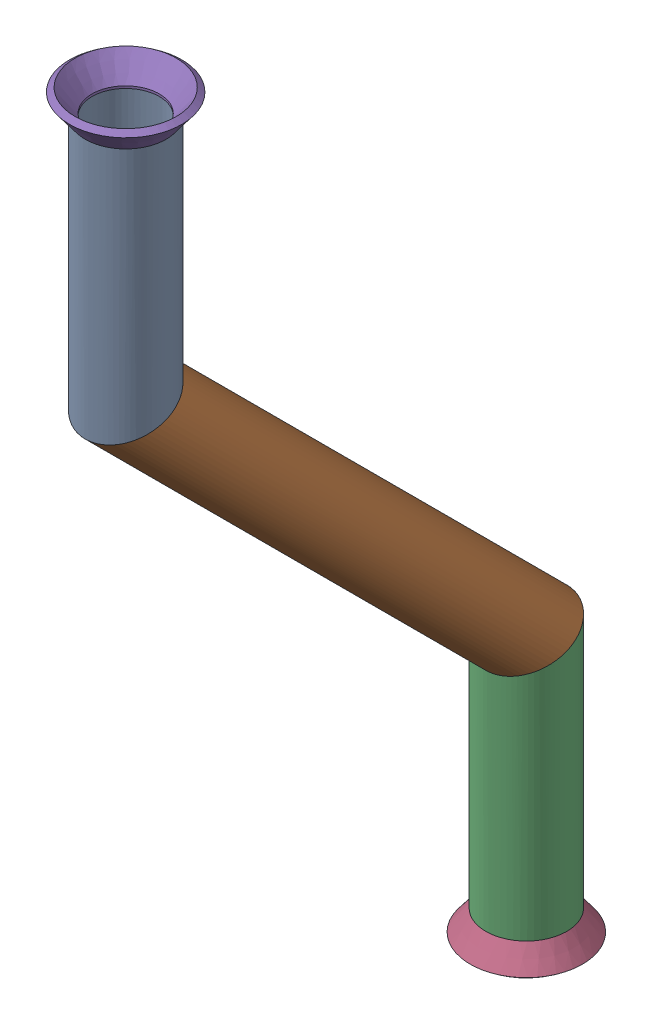
SolidWorks assembly Pipe 6, configuration Default. Lengths in mm.
Overall size (17.59 146.84 80.46).
3 component instances, 2 part files, 4 mates.
Components (placement in the parent):
- Part2-1: Part2 [Default<As Machined>] at origin size (12.7 139.06 75.56)
- Flared pipe end - .5 inch-1: Flared pipe end - .5 inch [Default<As Machined>] at (0 -189.578 244.7365) x (1 0 -0.00017) z (0 -1 0) size (17.59 17.59 3.89)
- Flared pipe end - .5 inch-2: Flared pipe end - .5 inch [Default<As Machined>] at (0 -50.5162 307.5983) x (1 0 0.00017) z (0 1 0) size (17.59 17.59 3.89)
Mates (geometry in assembly coordinates):
- Coincident1029: coincident: plane of Part2-1 through (0 -189.578 244.7365) normal (0 -1 0); plane of Flared pipe end - .5 inch-1 through (0.0009 -189.578 250.0197) normal (0 1 0)
- Concentric657: concentric: circle of Part2-1; circle of Flared pipe end - .5 inch-1
- Coincident1027: coincident: plane of Part2-1 through (0 -50.5162 307.5983) normal (0 1 0); plane of Flared pipe end - .5 inch-2 through (0.0009 -50.5162 302.3151) normal (0 -1 0)
- Concentric656: concentric: circle of Part2-1; circle of Flared pipe end - .5 inch-2
